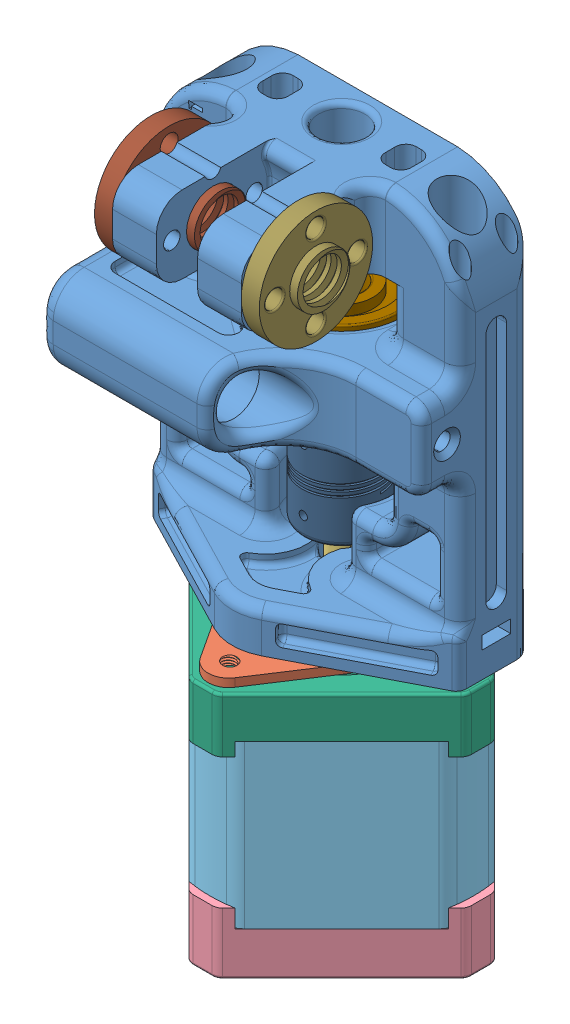
SolidWorks assembly lead motor assy, configuration Default. Lengths in mm.
Overall size (60.87 132.9 61.87).
17 component instances, 12 part files, 14 mates.
Components (placement in the parent):
- x motor lead-1: x motor lead [Default] at (1.0016 21.1815 58.4436) size (60.87 77.79 39.41)
- Nema 17 Damper v2-1: Nema 17 Damper v2 [Default] at (1.0013 -26.8185 65.4436) x (0 0 -1) z (-1 0 0) size (52.04 7.74 51.84)
- 17HM19-2004S-1: 17HM19-2004S [Default] at (-7.0366 -101.7185 75.882) x (0.703073 0 -0.711118) z (0.711118 0 0.703073) size (42.24 72 42.24)
  - nema17_shaft_17HM19-2004S-1: nema17_shaft_17HM19-2004S [Default] at (13.0746 21 -1.623) x (-0.412738 0 0.91085) z (-0.91085 0 -0.412738) size (5 72 5)
  - nema17_bottom_17HM19-2004S-1: nema17_bottom_17HM19-2004S [Default] at (13.0746 21 -1.623) x (0.999984 0 0.005702) z (-0.005702 0 0.999984) size (42 12 42)
  - nema17_middle_17HM19-2004S-1: nema17_middle_17HM19-2004S [Default] at (13.0746 29.5 -1.623) x (0.999984 0 0.005702) z (-0.005702 0 0.999984) size (42 31.5 42)
  - nema17_top_17HM19-2004S-1: nema17_top_17HM19-2004S [Default] at (13.0746 61 -1.623) x (0.999984 0 0.005702) z (-0.005702 0 0.999984) size (42 12.6 42)
  - radial ball bearing_68_din_DIN 625 - 625 - 8,SI,NC,8_68-1: radial ball bearing_68_din_DIN 625 - 625 - 8,SI,NC,8_68 [Default] at (13.0746 26 -1.623) x (0 -1 0) z (0 0 1) size (5.01 16 16)
  - radial ball bearing_68_din_DIN 625 - 625 - 8,SI,NC,8_68-2: radial ball bearing_68_din_DIN 625 - 625 - 8,SI,NC,8_68 [Default] at (13.0746 67.1 -1.623) x (0 1 0) z (0 0 1) size (5.01 16 16)
  - countersunk flat head cross recess screw_din_ISO 7046-1 - M3 x 30 - Z --- 30N-1: countersunk flat head cross recess screw_din_ISO 7046-1 - M3 x 30 - Z --- 30N [Default] at (28.4859 21.6 13.9651) x (0 1 0) z (0.546944 0 -0.837169) size (30 5.5 5.5)
  - countersunk flat head cross recess screw_din_ISO 7046-1 - M3 x 30 - Z --- 30N-2: countersunk flat head cross recess screw_din_ISO 7046-1 - M3 x 30 - Z --- 30N [Default] at (28.6627 21.6 -17.0344) x (0 1 0) z (0.546944 0 -0.837169) size (30 5.5 5.5)
  - countersunk flat head cross recess screw_din_ISO 7046-1 - M3 x 30 - Z --- 30N-3: countersunk flat head cross recess screw_din_ISO 7046-1 - M3 x 30 - Z --- 30N [Default] at (-2.5136 21.6 13.7883) x (0 1 0) z (0.546944 0 -0.837169) size (30 5.5 5.5)
  - countersunk flat head cross recess screw_din_ISO 7046-1 - M3 x 30 - Z --- 30N-4: countersunk flat head cross recess screw_din_ISO 7046-1 - M3 x 30 - Z --- 30N [Default] at (-2.3368 21.6 -17.2112) x (0 1 0) z (0.546944 0 -0.837169) size (30 5.5 5.5)
- instrument ball bearing_68_iso-1: instrument ball bearing_68_iso [ISO 1224 - 100822 - R,8,SI,NC,8_68] at (1.0016 18.6815 65.4436) x (0 1 0) z (0 0 1) size (7 22 22)
- 5-8 small-1: 5-8 small [Default] at (1.0016 -17.8185 65.4433) x (1 0 0) z (0 1 0) size (15.39 15.39 20)
- LeadScrew Nut 8mm x 2mmPitch (2)-1: LeadScrew Nut 8mm x 2mmPitch (2) [Default] at (-14.9984 41.1815 86.4436) x (0 0 1) z (-1 0 0) size (22 22 16.05)
- LeadScrew Nut 8mm x 2mmPitch-1: LeadScrew Nut 8mm x 2mmPitch [Default] at (17.0016 41.1815 86.4436) x (0 0 -1) z (1 0 0) size (22 22 16.05)
Mates (geometry in assembly coordinates):
- Coincidente1: coincident anti-aligned: plane of x motor lead-1 through (22.9219 -26.8185 65.4436) normal (0 -1 0); plane of Nema 17 Damper v2-1 through (1.0013 -26.8185 65.4436) normal (0 1 0)
- Concentrico1: concentric aligned: cylinder of x motor lead-1 through (-20.9187 -23.8185 65.4436) axis (0 -1 0) radius 1.6; cylinder of Nema 17 Damper v2-1 through (-20.9187 -26.8185 65.4436) axis (0 -1 0) radius 1.75
- Concentrico2: concentric aligned: cylinder of x motor lead-1 through (22.9219 -23.8185 65.4436) axis (0 -1 0) radius 1.6; cylinder of Nema 17 Damper v2-1 through (22.9213 -26.8185 65.4436) axis (0 -1 0) radius 1.75
- Coincidente2: coincident aligned: plane of Nema 17 Damper v2-1 through (1.0013 -32.7185 65.4436) normal (0 1 0); plane of 17HM19-2004S-1/nema17_top_17HM19-2004S-1 through (1.0016 -32.7185 65.4433) normal (0 1 0)
- Concentrico3: concentric aligned: cylinder of x motor lead-1 through (1.0016 48.6825 65.4436) axis (0 -1 0) radius 3.25; cylinder of 17HM19-2004S-1/nema17_shaft_17HM19-2004S-1 through (1.0016 -8.7185 65.4433) axis (0 -1 0) radius 2.5
- Concentrico4: concentric aligned: cylinder of Nema 17 Damper v2-1 through (1.0013 -31.1185 87.3636) axis (0 -1 0) radius 4; cylinder of 17HM19-2004S-1/nema17_top_17HM19-2004S-1 through (1.0013 -32.7185 87.3636) axis (0 -1 0) radius 1.25
- Concentrico5: concentric anti-aligned: cylinder of x motor lead-1 through (1.0016 61.1815 65.4436) axis (0 -1 0) radius 4.5; cylinder of instrument ball bearing_68_iso-1 through (1.0016 -1.956 65.4436) axis (0 1 0) radius 6.1
- Coincidente3: coincident anti-aligned: plane of x motor lead-1 through (1.0016 15.1815 65.4436) normal (0 1 0); plane of instrument ball bearing_68_iso-1 through (-7.8984 15.1815 65.4436) normal (0 -1 0)
- Distanza1: distance = 3 mm anti-aligned: plane of 5-8 small-1 through (1.0016 -17.8185 65.4433) normal (0 -1 0); plane of x motor lead-1 through (31.0016 -20.8185 87.9436) normal (0 1 0)
- Concentrico6: concentric anti-aligned: cylinder of 17HM19-2004S-1/nema17_shaft_17HM19-2004S-1 through (1.0016 -8.7185 65.4433) axis (0 -1 0) radius 2.5; cylinder of 5-8 small-1 through (1.0016 -7.8185 65.4433) axis (0 1 0) radius 4
- Coincidente4: coincident anti-aligned: plane of x motor lead-1 through (-11.4984 41.1815 86.4436) normal (-1 0 0); plane of LeadScrew Nut 8mm x 2mmPitch (2)-1 through (-11.4984 41.1815 86.4436) normal (1 0 0)
- Concentrico8: concentric aligned: cylinder of x motor lead-1 through (31.0026 41.1815 86.4436) axis (-1 0 0) radius 5.15; cylinder of LeadScrew Nut 8mm x 2mmPitch (2)-1 through (-11.4984 41.1815 86.4436) axis (-1 0 0) radius 11
- Coincidente5: coincident anti-aligned: plane of x motor lead-1 through (13.5016 41.1815 86.4436) normal (1 0 0); plane of LeadScrew Nut 8mm x 2mmPitch-1 through (13.5016 41.1815 86.4436) normal (-1 0 0)
- Concentrico9: concentric anti-aligned: cylinder of x motor lead-1 through (31.0026 41.1815 86.4436) axis (-1 0 0) radius 5.15; cylinder of LeadScrew Nut 8mm x 2mmPitch-1 through (3.5016 41.1815 86.4436) axis (1 0 0) radius 5.1
